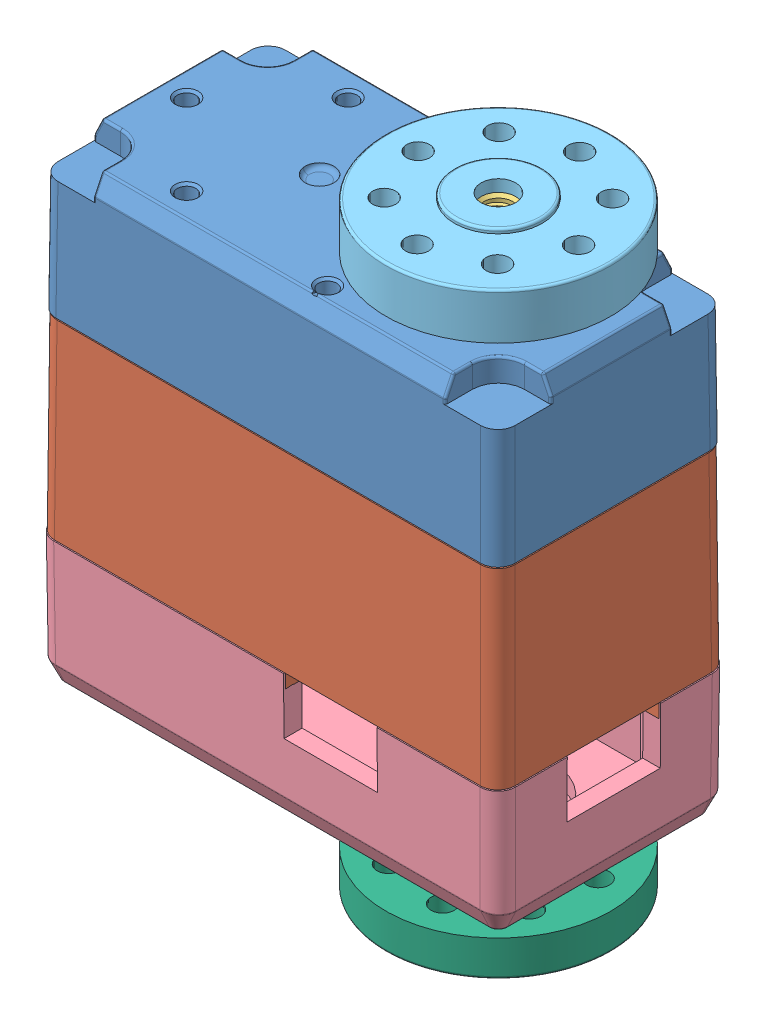
SolidWorks assembly 224or824, configuration 默认. Lengths in mm.
Overall size (43.81 52.54 27.58).
7 component instances, 6 part files, 0 mates.
Components (placement in the parent):
- 224or824.STEP-1: 224or824.STEP [默认] at origin size (43.81 52.54 27.58)
  - SG.STEP-1: SG.STEP [默认] at origin size (39.8 13.75 19.9)
  - ZK.STEP-1: ZK.STEP [默认] at origin size (39.93 17.8 20.03)
  - GE.STEP-1: GE.STEP [默认] at (10 10.8 0) x (0 0 -1) z (0 -1 0) size (17.3 17.3 15.8)
  - dg-tu-ck.STEP-1: dg-tu-ck.STEP [默认] at origin size (40.05 16.77 20.15)
  - ______.STEP-1: ______.STEP [默认] at (10 21.9777 0) x (-0.711921 0 0.70226) z (-0.70226 0 -0.711921) size (19.5 4.4 19.5)
  - ______-0.STEP-1: ______-0.STEP [默认] at (10 -22.6667 0) x (-0.872764 0 -0.488143) z (-0.488143 0 0.872764) size (19.5 3.5 19.5)
